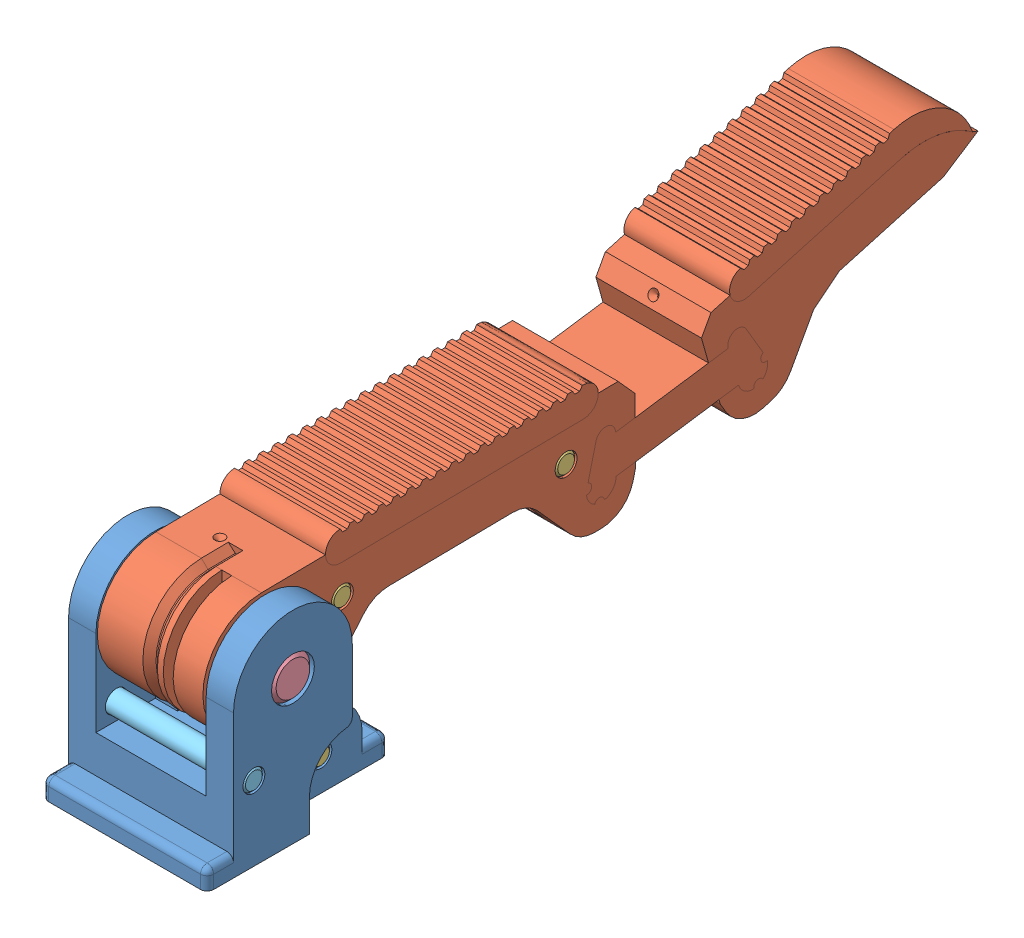
SolidWorks assembly block_finger_pf_t, configuration Default. Lengths in mm.
Overall size (25.4 45.69 121.76).
10 component instances, 8 part files, 18 mates.
Components (placement in the parent):
- c1_t-1: c1_t [Default] at origin size (25 30.67 32)
- finger_pf_t-1: finger_pf_t [Default] at (-0.15 21.67 -14.7858) x (1 0 0) z (0 -0.013363 0.999911) size (16 29.93 117.65)
- 98381A472 D1-8 L5-8-1: 98381A472 D1-8 L5-8 [98381A472] at (-0.0875 23.995 -26.9308) size (15.88 3.17 3.17)
- 98381A472 D1-8 L5-8-2: 98381A472 D1-8 L5-8 [98381A472] at (-0.0875 24.448 -60.8289) size (15.88 3.17 3.17)
- 98381A542 D1-4 L1-1: 98381A542 D1-4 L1 [98381A542] at (-0.2 21.67 -14.7858) size (25.4 6.35 6.35)
- 98381A475 D1-8 L1-1: 98381A475 D1-8 L1 [98381A475] at (-0.2 11.2575 -8.8732) size (25.4 3.17 3.17)
- 98381A472 D1-8 L5-8-3: 98381A472 D1-8 L5-8 [98381A472] at (0.0625 4.925 -23.535) size (15.88 3.17 3.17)
- 93365A120 4-40 insert-1: 93365A120 4-40 insert [93365A120] at (-0.15 27.5639 -100.2943) x (1 0 0) z (0 0.622567 -0.782567) size (4.37 3.82 4.37)
- 91253A106 4-40 L1-4 countersunk-1: 91253A106 4-40 L1-4 countersunk [91253A106] at (-0.15 25.9039 -101.6148) x (1 0 0) z (0 -0.782567 -0.622567) size (6.48 6.48 6.63)
- 3434T31 - nylon pulley-1: 3434T31 - nylon pulley [Default] at (-0.15 4.925 -23.535) x (0 -0.840446 -0.541896) z (0 -0.541896 0.840446) size (9.5 2.4 9.5)
Mates (geometry in assembly coordinates):
- Concentric1: concentric aligned: cylinder of c1_t-1 through (-12.5 21.67 -14.7858) axis (1 0 0) radius 3.25; cylinder of 98381A542 D1-4 L1-1 through (-12.9 21.67 -14.7858) axis (1 0 0) radius 3.175
- Coincident1: coincident aligned: plane of c1_t-1 through (12.5 21.67 -14.7858) normal (1 0 0); plane of 98381A542 D1-4 L1-1 through (12.5 21.67 -14.7858) normal (1 0 0)
- Concentric2: concentric aligned: cylinder of finger_pf_t-1 through (-8.15 21.67 -14.7858) axis (1 0 0) radius 3.35; cylinder of 98381A542 D1-4 L1-1 through (-12.9 21.67 -14.7858) axis (1 0 0) radius 3.175
- Distance1: distance = 0.2 mm anti-aligned: plane of c1_t-1 through (-8.35 21.67 -14.7858) normal (1 0 0); plane of finger_pf_t-1 through (-8.15 21.67 -14.7858) normal (-1 0 0)
- Concentric3: concentric aligned: cylinder of finger_pf_t-1 through (-8.15 23.995 -26.9308) axis (1 0 0) radius 1.6625; cylinder of 98381A472 D1-8 L5-8-1 through (-8.025 23.995 -26.9308) axis (1 0 0) radius 1.5875
- Coincident3: coincident aligned: plane of finger_pf_t-1 through (7.85 21.67 -14.7858) normal (1 0 0); plane of 98381A472 D1-8 L5-8-1 through (7.85 23.995 -26.9308) normal (1 0 0)
- Concentric4: concentric aligned: cylinder of finger_pf_t-1 through (-8.15 24.448 -60.8289) axis (1 0 0) radius 1.6625; cylinder of 98381A472 D1-8 L5-8-2 through (-8.025 24.448 -60.8289) axis (1 0 0) radius 1.5875
- Coincident4: coincident aligned: plane of finger_pf_t-1 through (7.85 21.67 -14.7858) normal (1 0 0); plane of 98381A472 D1-8 L5-8-2 through (7.85 24.448 -60.8289) normal (1 0 0)
- Concentric5: concentric aligned: cylinder of c1_t-1 through (-12.5 4.925 -23.535) axis (1 0 0) radius 1.6625; cylinder of 98381A472 D1-8 L5-8-3 through (-7.875 4.925 -23.535) axis (1 0 0) radius 1.5875
- Coincident5: coincident aligned: plane of c1_t-1 through (8 4.925 -23.535) normal (1 0 0); plane of 98381A472 D1-8 L5-8-3 through (8 4.925 -23.535) normal (1 0 0)
- Concentric6: concentric aligned: cylinder of c1_t-1 through (-12.5 11.2575 -8.8732) axis (1 0 0) radius 1.6625; cylinder of 98381A475 D1-8 L1-1 through (-12.9 11.2575 -8.8732) axis (1 0 0) radius 1.5875
- Coincident6: coincident aligned: plane of c1_t-1 through (12.5 21.67 -14.7858) normal (1 0 0); plane of 98381A475 D1-8 L1-1 through (12.5 11.2575 -8.8732) normal (1 0 0)
- Concentric7: concentric aligned: cylinder of finger_pf_t-1 through (-0.15 31.0854 -97.4927) axis (0 -0.782567 -0.622567) radius 1.85; circle of 93365A120 4-40 insert-1
- Coincident7: coincident aligned: plane of finger_pf_t-1 through (-13.15 26.0075 -98.3378) normal (0 -0.782567 -0.622567); plane of 93365A120 4-40 insert-1 through (-0.15 27.5639 -100.2943) normal (0 -0.782567 -0.622567)
- Concentric8: concentric anti-aligned: circle of 93365A120 4-40 insert-1; circle of 91253A106 4-40 L1-4 countersunk-1
- Coincident8: coincident: circle of 93365A120 4-40 insert-1; cone of 91253A106 4-40 L1-4 countersunk-1 through (-0.15 27.5537 -100.3023) axis (0 0.782567 0.622567)
- Concentric9: concentric anti-aligned: cylinder of 98381A472 D1-8 L5-8-3 through (-7.875 4.925 -23.535) axis (1 0 0) radius 1.5875; cylinder of 3434T31 - nylon pulley-1 through (-0.15 4.925 -23.535) axis (-1 0 0) radius 1.5
- Distance2: distance = 0.2 mm anti-aligned: plane of c1_t-1 through (-1.55 4.925 -23.535) normal (1 0 0); plane of 3434T31 - nylon pulley-1 through (-1.35 3.6643 -24.3478) normal (-1 0 0)
